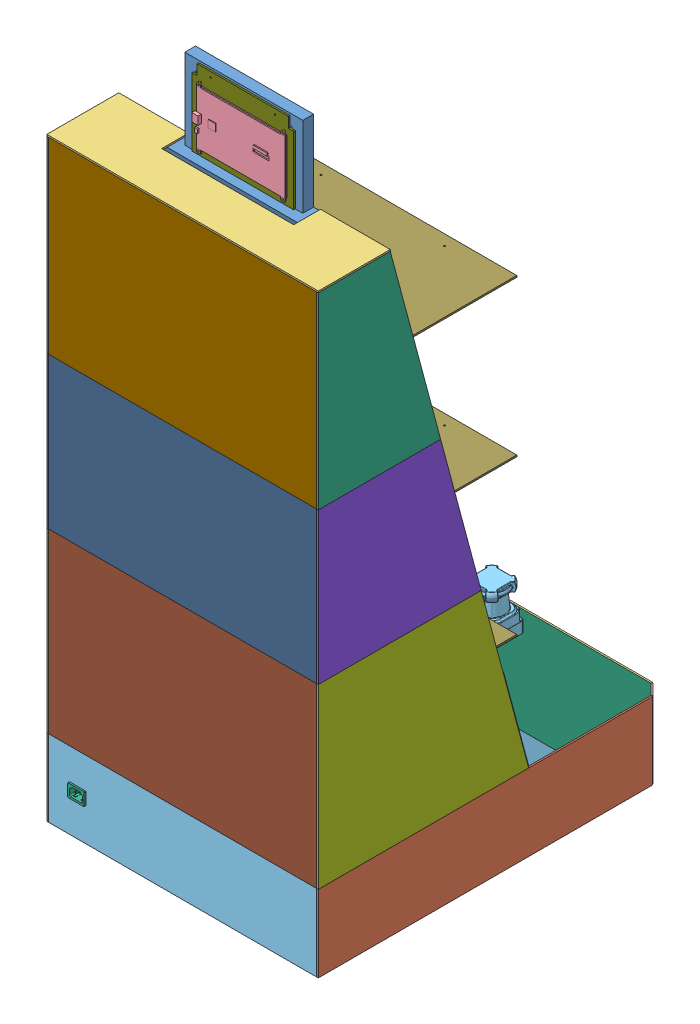
SolidWorks assembly Assembly, configuration Default. Lengths in mm.
Overall size (506 1255.93 649).
43 component instances, 28 part files, 89 mates.
Components (placement in the parent):
- Structure-1: Structure [Default] at origin size (500 1255.93 640)
- Bottom_Side_Cover-1: Bottom_Side_Cover [Default] at (553.019 71.5 262.438) size (3 143 623)
- Bottom_Side_Cover-2: Bottom_Side_Cover [Default] at (50.019 71.5 262.438) size (3 143 623)
- Bottom_Front_Cover-1: Bottom_Front_Cover [Default] at (303.019 71.5 -72.062) size (460 143 3)
- Bottom_Chamfer_Cover-1: Bottom_Chamfer_Cover [Default] at (606.1809 0 -0.1428) x (0.707107 0 0.707107) z (-0.707107 0 0.707107) size (28.28 143 3)
- Bottom_Chamfer_Cover-2: Bottom_Chamfer_Cover [Default] at (121.9382 0 -122.2239) x (0.707107 0 -0.707107) z (0.707107 0 0.707107) size (28.28 143 3)
- Bottom_Back_Cover-1: Bottom_Back_Cover [Default] at (303.019 71.5 570.938) size (500 143 3)
- Top_Side_Cover_1-1: Top_Side_Cover_1 [Default] at (53.019 930.7205 459.9014) x (-1 0 0) z (0 0 -1) size (3 350.41 228.07)
- Top_Side_Cover_3-1: Top_Side_Cover_3 [Default] at (53.019 308.3272 377.8399) x (-1 0 0) z (0 0 -1) size (3 330.65 392.2)
- Top_Side_Cover_2-1: Top_Side_Cover_2 [Default] at (53.019 614.5848 422.1392) x (-1 0 0) z (0 0 -1) size (3 281.86 303.6)
- Top_Side_Cover_1-3: Top_Side_Cover_1 [Default] at (556.019 930.7205 459.9014) x (-1 0 0) z (0 0 -1) size (3 350.41 228.07)
- Top_Side_Cover_3-2: Top_Side_Cover_3 [Default] at (556.019 308.3272 377.8399) x (-1 0 0) z (0 0 -1) size (3 330.65 392.2)
- Top_Side_Cover_2-2: Top_Side_Cover_2 [Default] at (556.019 614.5848 422.1392) x (-1 0 0) z (0 0 -1) size (3 281.86 303.6)
- Top_Back_Cover_1-2: Top_Back_Cover_1 [Default] at (303.019 930.7205 573.938) x (0 0 -1) z (1 0 0) size (3 350.41 500)
- Top_Back_Cover_2-1: Top_Back_Cover_2 [Default] at (303.019 614.5848 573.938) x (0 0 -1) z (1 0 0) size (3 281.86 500)
- Top_Back_Cover_3-1: Top_Back_Cover_3 [Default] at (303.019 308.3272 573.938) x (0 0 -1) z (1 0 0) size (3 330.65 500)
- Plate-1: Plate [Default] at (368.3086 923.0814 322.6754) size (460 3 390.53)
- Plate-2: Plate [Default] at (368.3086 633.3037 322.6754) size (460 3 390.53)
- Plate-3: Plate [Default] at (368.3086 343.5259 322.6754) size (460 3 390.53)
- Bottom_Angle_Cover_1-1: Bottom_Angle_Cover_1 [Default] at (303.019 231.763 205.5258) x (-1 0 0) z (0 -0.965926 -0.258819) size (500 3 185)
- Bottom_Angle_Cover_2-1: Bottom_Angle_Cover_2 [Default] at (303.019 140 153.0402) size (500 3 50)
- System_Monitor_Support-1: System_Monitor_Support [Default] at (333.9495 140 29.488) size (500 3 197.1)
- LCD_Support-1: LCD_Support [Default] at (304.064 1178.9258 462.757) x (-1 0 0) z (0 -1 0) size (190 18 146)
- System_Controller_Support-1: System_Controller_Support [Default] at (303.019 140 395.938) size (500 3 345)
- Bottom_Battery_Support_2-1: Bottom_Battery_Support_2 [Default] at (303.019 20 453.438) size (340 3 195)
- Bottom_Battery_Support_1-1: Bottom_Battery_Support_1 [Default] at (303.019 20 148.438) size (500 3 235)
- Plate_Support-1: Plate_Support [Default] at (93.019 921.0814 560.938) size (40 40 20)
- Plate_Support-2: Plate_Support [Default] at (513.0183 631.3037 560.938) x (-1 0 0) z (0 0 -1) size (40 40 20)
- Plate_Support-3: Plate_Support [Default] at (93.019 631.3037 560.938) size (40 40 20)
- Plate_Support-4: Plate_Support [Default] at (513.0183 921.0814 560.938) x (-1 0 0) z (0 0 -1) size (40 40 20)
- Plate_Support-5: Plate_Support [Default] at (93.019 341.5259 560.938) size (40 40 20)
- Plate_Support-6: Plate_Support [Default] at (513.0183 341.5259 560.938) x (-1 0 0) z (0 0 -1) size (40 40 20)
- Top_Top_Cover-1: Top_Top_Cover [Default] at (347.3528 1105.9258 497.3106) size (506 3 134.18)
- LCD_Adafruit_HDMI_7inch-1: LCD_Adafruit_HDMI_7inch [Défaut] at (304.389 1170.0258 467.157) x (-1 0 0) z (0 0 -1) size (167.43 114.5 14.01)
- LIDAR_Hokuyo_UTM_30LX-1: LIDAR_Hokuyo_UTM_30LX [0] at (303.019 143 -2.562) x (0 0 -1) z (1 0 0) size (80 87 60)
- AC_Power_Socket-1: AC_Power_Socket [預設] at (107.269 72.9571 576.938) x (-1 0 0) z (0 0 -1) size (31 24 26.5)
- Voltage_Display-1: Voltage_Display [Valor predeterminado] at (345.659 283.7304 232.1015) x (-1 0 0) z (0 0.258819 -0.965926) size (47.75 28.83 22.12)
- Voltage_Display-2: Voltage_Display [Valor predeterminado] at (260.379 283.7304 232.1015) x (-1 0 0) z (0 0.258819 -0.965926) size (47.75 28.83 22.12)
- E_Stop_Button-1: E_Stop_Button [Default] at (133.019 143 -2.562) x (0 0 -1) z (1 0 0) size (39 70.54 39)
- Battery_Switch-1: Battery_Switch [Default] at (154.019 143 61.438) x (1 0 0) z (0 1 0) size (26 34 36.77)
- Battery_Switch-2: Battery_Switch [Default] at (112.019 143 61.438) x (1 0 0) z (0 1 0) size (26 34 36.77)
- LED_Indicator-1: LED_Indicator [Default] at (154.019 148.5 93.438) x (0 -1 0) z (0.023761 0 -0.999718) size (43 18.7 18.7)
- LED_Indicator-2: LED_Indicator [Default] at (112.019 148.5 93.438) x (0 -1 0) z (0.077267 0 0.99701) size (43 18.7 18.7)
Mates (geometry in assembly coordinates):
- Coincident5: coincident aligned: line of Structure-1 through (553.019 0 570.938) axis (0 0 -1); line of Bottom_Side_Cover-1 through (553.019 0 573.938) axis (0 0 -1)
- Coincident6: coincident aligned: line of Structure-1 through (553.019 120 -49.062) axis (0 1 0); line of Bottom_Side_Cover-1 through (553.019 0 -49.062) axis (0 1 0)
- Coincident7: coincident anti-aligned: line of Structure-1 through (53.019 140 -49.062) axis (0 -1 0); line of Bottom_Side_Cover-2 through (53.019 0 -49.062) axis (0 1 0)
- Coincident8: coincident anti-aligned: line of Structure-1 through (53.019 0 -49.062) axis (0 0 1); line of Bottom_Side_Cover-2 through (53.019 0 573.938) axis (0 0 -1)
- Coincident10: coincident anti-aligned: line of Structure-1 through (533.019 140 -69.062) axis (0 -1 0); line of Bottom_Front_Cover-1 through (533.019 0 -69.062) axis (0 1 0)
- Coincident11: coincident anti-aligned: line of Structure-1 through (533.019 0 -69.062) axis (-1 0 0); line of Bottom_Front_Cover-1 through (73.019 0 -69.062) axis (1 0 0)
- Coincident12: coincident aligned: line of Structure-1 through (533.019 0 -69.062) axis (0.707107 0 0.707107); line of Bottom_Chamfer_Cover-1 through (533.019 0 -69.062) axis (0.707107 0 0.707107)
- Coincident13: coincident aligned: line of Bottom_Side_Cover-1 through (553.019 0 -49.062) axis (0 1 0); line of Bottom_Chamfer_Cover-1 through (553.019 0 -49.062) axis (0 1 0)
- Coincident14: coincident anti-aligned: line of Bottom_Side_Cover-2 through (53.019 0 -49.062) axis (0 1 0); line of Bottom_Chamfer_Cover-2 through (53.019 143 -49.062) axis (0 -1 0)
- Coincident15: coincident aligned: line of Structure-1 through (53.019 0 -49.062) axis (0.707107 0 -0.707107); line of Bottom_Chamfer_Cover-2 through (53.019 0 -49.062) axis (0.707107 0 -0.707107)
- Coincident16: coincident aligned: line of Structure-1 through (53.019 0 570.938) axis (1 0 0); line of Bottom_Back_Cover-1 through (53.019 0 570.938) axis (1 0 0)
- Coincident17: coincident anti-aligned: line of Bottom_Side_Cover-1 through (553.019 143 573.938) axis (0 -1 0); line of Bottom_Back_Cover-1 through (553.019 0 573.938) axis (0 1 0)
- Coincident18: coincident aligned: line of Structure-1 through (53.019 1105.9258 439.757) axis (0 -0.965926 -0.258819); line of Top_Side_Cover_1-1 through (53.019 1105.9258 439.757) axis (0 -0.965926 -0.258819)
- Coincident19: coincident anti-aligned: line of Structure-1 through (53.019 1105.9258 439.757) axis (0 0 1); line of Top_Side_Cover_1-1 through (53.019 1105.9258 573.938) axis (0 0 -1)
- Coincident20: coincident aligned: line of Structure-1 through (53.019 1105.9258 439.757) axis (0 -0.965926 -0.258819); line of Top_Side_Cover_3-1 through (53.019 473.6543 270.3404) axis (0 -0.965926 -0.258819)
- Coincident21: coincident anti-aligned: line of Structure-1 through (53.019 473.6543 310.3404) axis (0 0 1); line of Top_Side_Cover_3-1 through (53.019 473.6543 573.938) axis (0 0 -1)
- Coincident22: coincident aligned: line of Structure-1 through (53.019 1105.9258 439.757) axis (0 -0.965926 -0.258819); line of Top_Side_Cover_2-1 through (53.019 755.5152 345.8648) axis (0 -0.965926 -0.258819)
- Coincident23: coincident anti-aligned: line of Top_Side_Cover_1-1 through (53.019 755.5152 345.8648) axis (0 0 1); line of Top_Side_Cover_2-1 through (53.019 755.5152 573.938) axis (0 0 -1)
- Coincident26: coincident aligned: line of Structure-1 through (553.019 1105.9258 439.757) axis (0 -0.965926 -0.258819); line of Top_Side_Cover_1-3 through (553.019 1105.9258 439.757) axis (0 -0.965926 -0.258819)
- Coincident27: coincident aligned: line of Structure-1 through (553.019 1105.9258 570.938) axis (0 0 -1); line of Top_Side_Cover_1-3 through (553.019 1105.9258 573.938) axis (0 0 -1)
- Coincident28: coincident aligned: line of Structure-1 through (553.019 1105.9258 439.757) axis (0 -0.965926 -0.258819); line of Top_Side_Cover_3-2 through (553.019 473.6543 270.3404) axis (0 -0.965926 -0.258819)
- Coincident29: coincident anti-aligned: line of Structure-1 through (553.019 473.6543 310.3404) axis (0 0 1); line of Top_Side_Cover_3-2 through (553.019 473.6543 573.938) axis (0 0 -1)
- Coincident30: coincident aligned: line of Structure-1 through (553.019 1105.9258 439.757) axis (0 -0.965926 -0.258819); line of Top_Side_Cover_2-2 through (553.019 755.5152 345.8648) axis (0 -0.965926 -0.258819)
- Coincident31: coincident anti-aligned: line of Top_Side_Cover_1-3 through (553.019 755.5152 345.8648) axis (0 0 1); line of Top_Side_Cover_2-2 through (553.019 755.5152 573.938) axis (0 0 -1)
- Coincident35: coincident aligned: line of Structure-1 through (53.019 1105.9258 570.938) axis (1 0 0); line of Top_Back_Cover_1-2 through (53.019 1105.9258 570.938) axis (1 0 0)
- Coincident37: coincident anti-aligned: line of Structure-1 through (53.019 1105.9258 570.938) axis (0 -1 0); line of Top_Back_Cover_1-2 through (53.019 755.5152 570.938) axis (0 1 0)
- Coincident38: coincident anti-aligned: line of Structure-1 through (533.019 755.5152 570.938) axis (-1 0 0); line of Top_Back_Cover_2-1 through (53.019 755.5152 570.938) axis (1 0 0)
- Coincident39: coincident aligned: line of Structure-1 through (553.019 1105.9258 570.938) axis (0 -1 0); line of Top_Back_Cover_2-1 through (553.019 755.5152 570.938) axis (0 -1 0)
- Coincident40: coincident anti-aligned: line of Structure-1 through (533.019 473.6543 570.938) axis (-1 0 0); line of Top_Back_Cover_3-1 through (53.019 473.6543 570.938) axis (1 0 0)
- Coincident41: coincident anti-aligned: line of Structure-1 through (53.019 1105.9258 570.938) axis (0 -1 0); line of Top_Back_Cover_3-1 through (53.019 143 570.938) axis (0 1 0)
- Coincident42: coincident aligned: line of Structure-1 through (428.019 923.0814 180.938) axis (-1 0 0); line of Plate-1 through (533.0183 923.0814 180.938) axis (-1 0 0)
- Coincident43: coincident anti-aligned: line of Structure-1 through (73.019 923.0814 425.405) axis (0 0 -1); line of Plate-1 through (73.019 923.0814 180.938) axis (0 0 1)
- Coincident44: coincident aligned: line of Structure-1 through (428.019 633.3037 180.938) axis (-1 0 0); line of Plate-2 through (533.0183 633.3037 180.938) axis (-1 0 0)
- Coincident45: coincident aligned: line of Structure-1 through (73.019 633.3037 327.7593) axis (0 0 1); line of Plate-2 through (73.019 633.3037 180.938) axis (0 0 1)
- Coincident46: coincident aligned: line of Structure-1 through (428.019 343.5259 180.938) axis (-1 0 0); line of Plate-3 through (533.0183 343.5259 180.938) axis (-1 0 0)
- Coincident47: coincident aligned: line of Structure-1 through (73.019 343.5259 250.1136) axis (0 0 1); line of Plate-3 through (73.019 343.5259 180.938) axis (0 0 1)
- Coincident51: coincident aligned: line of Structure-1 through (553.019 140 180.938) axis (0 0 -1); line of Bottom_Angle_Cover_2-1 through (553.019 140 178.0402) axis (0 0 -1)
- Coincident52: coincident aligned: line of Structure-1 through (53.019 140 -49.062) axis (0 0 1); line of Bottom_Angle_Cover_2-1 through (53.019 140 128.0402) axis (0 0 1)
- Coincident53: coincident aligned: line of Structure-1 through (533.019 140 -69.062) axis (-1 0 0); line of System_Monitor_Support-1 through (533.019 140 -69.062) axis (-1 0 0)
- Coincident54: coincident aligned: line of Structure-1 through (553.019 140 180.938) axis (0 0 -1); line of System_Monitor_Support-1 through (553.019 140 128.038) axis (0 0 -1)
- Coincident56: coincident anti-aligned: plane of Structure-1 through (0 1105.9258 258.819) normal (0 1 0); plane of LCD_Support-1 through (389.064 1105.9258 459.757) normal (0 -1 0)
- Coincident57: coincident anti-aligned: plane of Structure-1 through (213.019 1255.9258 459.757) normal (0 0 1); plane of LCD_Support-1 through (304.064 1178.9258 459.757) normal (0 0 -1)
- Lock1: lock: unknown of Structure-1; unknown of LCD_Support-1
- Coincident58: coincident aligned: line of Structure-1 through (73.019 140 570.938) axis (1 0 0); line of System_Controller_Support-1 through (73.019 140 570.938) axis (1 0 0)
- Coincident59: coincident aligned: line of Structure-1 through (53.019 140 220.938) axis (0 0 1); line of System_Controller_Support-1 through (53.019 140 225.938) axis (0 0 1)
- Coincident60: coincident anti-aligned: line of Structure-1 through (453.019 20 475.938) axis (1 0 0); line of Bottom_Battery_Support_2-1 through (473.019 20 475.938) axis (-1 0 0)
- Coincident61: coincident aligned: line of Structure-1 through (133.019 20 475.938) axis (0 0 1); line of Bottom_Battery_Support_2-1 through (133.019 20 475.938) axis (0 0 1)
- Coincident62: coincident aligned: line of Structure-1 through (53.019 20 -24.062) axis (0 0 1); line of Bottom_Battery_Support_1-1 through (53.019 20 30.938) axis (0 0 1)
- Coincident63: coincident anti-aligned: line of Structure-1 through (133.019 20 30.938) axis (1 0 0); line of Bottom_Battery_Support_1-1 through (553.019 20 30.938) axis (-1 0 0)
- Coincident64: coordinate: point of Structure-1
- Coincident65: coincident aligned: line of Plate-1 through (73.019 923.0814 180.938) axis (0 0 1); line of Plate_Support-1 through (73.019 923.0814 550.938) axis (0 0 1)
- Coincident66: coincident aligned: line of Structure-1 through (73.019 1085.9258 550.938) axis (0 -1 0); line of Plate_Support-1 through (73.019 923.0814 550.938) axis (0 -1 0)
- Coincident69: coincident aligned: line of Plate-2 through (73.019 633.3037 180.938) axis (0 0 1); line of Plate_Support-3 through (73.019 633.3037 550.938) axis (0 0 1)
- Coincident70: coincident aligned: line of Structure-1 through (73.019 755.5152 550.938) axis (0 -1 0); line of Plate_Support-3 through (73.019 633.3037 550.938) axis (0 -1 0)
- Coincident72: coincident aligned: line of Plate-1 through (533.0183 923.0814 571.4695) axis (0 0 -1); line of Plate_Support-4 through (533.0183 923.0814 570.938) axis (0 0 -1)
- Coincident73: coincident aligned: line of Structure-1 through (533.019 1085.9258 550.938) axis (0 -1 0); line of Plate_Support-4 through (533.0183 923.0814 550.938) axis (0 -1 0)
- Coincident74: coincident aligned: line of Plate-2 through (533.0183 633.3037 571.4695) axis (0 0 -1); line of Plate_Support-2 through (533.0183 633.3037 570.938) axis (0 0 -1)
- Coincident75: coincident aligned: line of Structure-1 through (533.019 755.5152 550.938) axis (0 -1 0); line of Plate_Support-2 through (533.0183 633.3037 550.938) axis (0 -1 0)
- Coincident76: coincident aligned: line of Plate-3 through (73.019 343.5259 180.938) axis (0 0 1); line of Plate_Support-5 through (73.019 343.5259 550.938) axis (0 0 1)
- Coincident77: coincident aligned: line of Structure-1 through (73.019 453.6543 550.938) axis (0 -1 0); line of Plate_Support-5 through (73.019 343.5259 550.938) axis (0 -1 0)
- Coincident78: coincident aligned: line of Plate-3 through (533.0183 343.5259 571.4695) axis (0 0 -1); line of Plate_Support-6 through (533.0183 343.5259 570.938) axis (0 0 -1)
- Coincident79: coincident aligned: line of Structure-1 through (533.019 453.6543 550.938) axis (0 -1 0); line of Plate_Support-6 through (533.0183 343.5259 550.938) axis (0 -1 0)
- Coincident80: coincident aligned: line of Structure-1 through (193.019 1105.9258 439.757) axis (-1 0 0); line of Top_Top_Cover-1 through (180.019 1105.9258 439.757) axis (-1 0 0)
- Coincident81: coincident anti-aligned: line of Top_Side_Cover_1-1 through (50.019 1105.9258 573.938) axis (0 0 -1); line of Top_Top_Cover-1 through (50.019 1105.9258 439.757) axis (0 0 1)
- Coincident82: coincident anti-aligned: line of LCD_Support-1 through (386.214 1220.0258 462.757) axis (-1 0 0); line of LCD_Adafruit_HDMI_7inch-1 through (221.914 1220.0258 462.757) axis (1 0 0)
- Coincident84: coincident anti-aligned: line of LCD_Support-1 through (221.914 1220.0258 462.757) axis (0 -1 0); line of LCD_Adafruit_HDMI_7inch-1 through (221.914 1120.0258 462.757) axis (0 1 0)
- Concentric1: concentric anti-aligned: circle of System_Monitor_Support-1; circle of LIDAR_Hokuyo_UTM_30LX-1
- Concentric2: concentric anti-aligned: circle of System_Monitor_Support-1; circle of LIDAR_Hokuyo_UTM_30LX-1
- Coincident85: coincident anti-aligned: plane of System_Monitor_Support-1 through (333.9495 143 29.488) normal (0 1 0); plane of LIDAR_Hokuyo_UTM_30LX-1 through (276.519 143 23.938) normal (0 -1 0)
- Coincident86: coincident aligned: line of Bottom_Back_Cover-1 through (93.019 67.2071 573.938) axis (0 1 0); line of AC_Power_Socket-1 through (93.019 67.2071 573.938) axis (0 1 0)
- Coincident88: coincident aligned: line of Bottom_Back_Cover-1 through (117.019 62.7071 573.938) axis (-1 0 0); line of AC_Power_Socket-1 through (117.019 62.7071 573.938) axis (-1 0 0)
- Coincident89: coincident aligned: line of Structure-1 through (553.019 140 180.938) axis (-1 0 0); line of Bottom_Angle_Cover_1-1 through (553.019 140 180.938) axis (-1 0 0)
- Coincident90: coincident aligned: line of Top_Side_Cover_3-2 through (553.019 473.6543 270.3404) axis (0 -0.965926 -0.258819); line of Bottom_Angle_Cover_1-1 through (553.019 318.6963 228.8195) axis (0 -0.965926 -0.258819)
- Coincident91: coincident: line of Bottom_Angle_Cover_1-1 through (553.019 140.7765 178.0402) axis (-1 0 0); plane of Bottom_Angle_Cover_2-1 through (553.019 143 178.0402) normal (0 0 1)
- Coincident92: coincident anti-aligned: line of Bottom_Angle_Cover_1-1 through (237.739 275.185 214.0549) axis (0 0.965926 0.258819); line of Voltage_Display-2 through (237.739 300.1542 220.7453) axis (0 -0.965926 -0.258819)
- Coincident93: coincident anti-aligned: line of Bottom_Angle_Cover_1-1 through (237.739 300.1542 220.7453) axis (1 0 0); line of Voltage_Display-2 through (247.969 300.1542 220.7453) axis (-1 0 0)
- Coincident94: coincident anti-aligned: line of Bottom_Angle_Cover_1-1 through (323.019 275.185 214.0549) axis (0 0.965926 0.258819); line of Voltage_Display-1 through (323.019 300.1542 220.7453) axis (0 -0.965926 -0.258819)
- Coincident95: coincident anti-aligned: line of Bottom_Angle_Cover_1-1 through (323.019 300.1542 220.7453) axis (1 0 0); line of Voltage_Display-1 through (333.249 300.1542 220.7453) axis (-1 0 0)
- Coincident98: coincident anti-aligned: line of System_Monitor_Support-1 through (143.019 143 47.438) axis (1 0 0); line of Battery_Switch-1 through (165.019 143 47.438) axis (-1 0 0)
- Coincident99: coincident anti-aligned: line of System_Monitor_Support-1 through (143.019 143 77.438) axis (0 0 -1); line of Battery_Switch-1 through (143.019 143 47.438) axis (0 0 1)
- Coincident100: coincident anti-aligned: line of System_Monitor_Support-1 through (101.019 143 47.438) axis (1 0 0); line of Battery_Switch-2 through (123.019 143 47.438) axis (-1 0 0)
- Coincident101: coincident anti-aligned: line of System_Monitor_Support-1 through (101.019 143 77.438) axis (0 0 -1); line of Battery_Switch-2 through (101.019 143 47.438) axis (0 0 1)
- Coincident109: coincident anti-aligned: plane of System_Monitor_Support-1 through (333.9495 143 29.488) normal (0 1 0); plane of LED_Indicator-2 through (112.019 143 93.438) normal (0 -1 0)
- Concentric10: concentric aligned: circle of System_Monitor_Support-1; circle of LED_Indicator-2
- Coincident110: coincident anti-aligned: plane of System_Monitor_Support-1 through (333.9495 143 29.488) normal (0 1 0); plane of LED_Indicator-1 through (154.019 143 93.438) normal (0 -1 0)
- Concentric11: concentric aligned: circle of System_Monitor_Support-1; circle of LED_Indicator-1
- Concentric13: concentric: circle of System_Monitor_Support-1; circle of E_Stop_Button-1
- Parallel1: parallel: line of System_Monitor_Support-1 through (53.019 140 -49.062) axis (0 0 1); line of E_Stop_Button-1 through (118.319 97.1 9.438) axis (0 0 -1)
- Coincident112: coincident anti-aligned: plane of System_Monitor_Support-1 through (333.9495 143 29.488) normal (0 1 0); plane of E_Stop_Button-1 through (133.019 143 -16.562) normal (0 -1 0)
